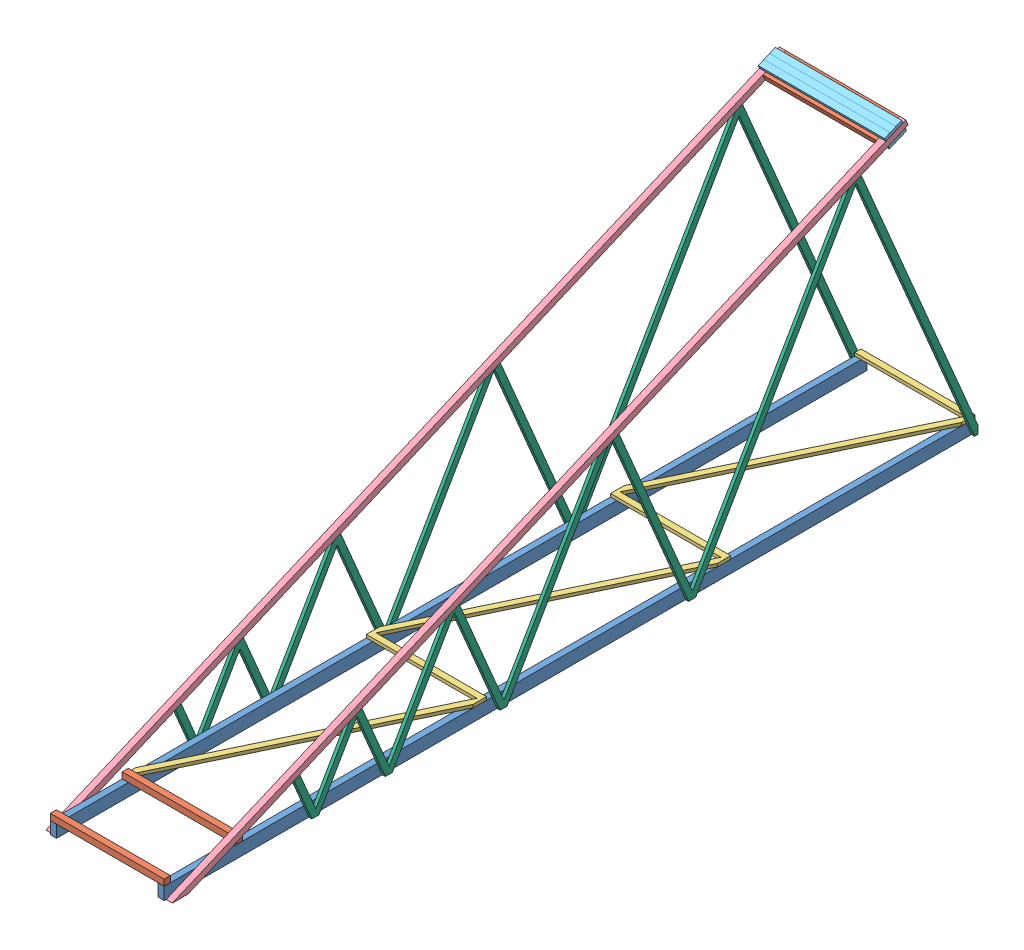
SolidWorks assembly V2 1-2, configuration Default. Lengths in mm.
Overall size (64.7 160.34 415).
20 component instances, 7 part files, 60 mates.
Components (placement in the parent):
- CompressionBeam-1: CompressionBeam [Default] at (128.4141 212.2584 116.772) size (3.17 6.35 415)
- CompressionBeam-2: CompressionBeam [Default] at (73.2391 212.2584 116.772) size (3.17 6.35 415)
- Part2^V2 1-2-1: Part2^V2 1-2 [Default] at (73.2391 212.2584 116.772) x (0 0 1) z (-1 0 0) (virtual)
- CompressionHorizontalBrace-1: CompressionHorizontalBrace [Default] at (73.2391 221.7834 531.772) x (0 -1 0) z (1 0 0) size (3.17 3.17 58.35)
- CompressionHorizontalBrace-2: CompressionHorizontalBrace [Default] at (73.2391 221.7834 494.947) x (0 -1 0) z (1 0 0) size (3.17 3.17 58.35)
- Part4^V2 1-2-1: Part4^V2 1-2 [Default] at (128.4141 218.6084 116.772) x (1 0 0) z (0 1 0) size (58.35 375 1.59) (virtual)
- Part5^V2 1-2-1: Part5^V2 1-2 [Default] at (73.2391 212.2584 116.772) x (0 0 1) z (-1 0 0) size (376.7 159.5 3.17) (virtual)
- CompressionHorizontalBrace-3: CompressionHorizontalBrace [Default] at (73.2391 369.274 161.1687) x (0 -0.920393 -0.390995) z (1 0 0) size (3.17 3.17 58.35)
- CompressionHorizontalBrace-4: CompressionHorizontalBrace [Default] at (73.2391 370.5154 158.2464) x (0 -0.920393 -0.390995) z (1 0 0) size (3.17 3.17 58.35)
- CompressionHorizontalBrace-5: CompressionHorizontalBrace [Default] at (73.2391 368.0326 164.0909) x (0 -0.920393 -0.390995) z (1 0 0) size (3.17 3.17 58.35)
- CompressionHorizontalBrace-6: CompressionHorizontalBrace [Default] at (73.2391 366.7912 167.0132) x (0 -0.920393 -0.390995) z (1 0 0) size (3.17 3.17 58.35)
- Part5^V2 1-2-2: Part5^V2 1-2 [Default] at (134.7641 212.2584 116.772) x (0 0 1) z (-1 0 0) size (376.7 159.5 3.17) (virtual)
- Part6^V2 1-2-1: Part6^V2 1-2 [Default] at (71.6516 366.621 167.4137) x (1 0 0) z (0 0.920393 0.390995) size (64.7 3.18 1.59) (virtual)
- Part6^V2 1-2-2: Part6^V2 1-2 [Default] at (71.6516 367.8625 164.4915) x (1 0 0) z (0 0.920393 0.390995) size (64.7 3.18 1.59) (virtual)
- Part6^V2 1-2-3: Part6^V2 1-2 [Default] at (71.6516 369.1039 161.5693) x (1 0 0) z (0 0.920393 0.390995) size (64.7 3.18 1.59) (virtual)
- Part6^V2 1-2-4: Part6^V2 1-2 [Default] at (71.6516 364.7205 159.7071) x (1 0 0) z (0 0.920393 0.390995) size (64.7 3.18 1.59) (virtual)
- Part6^V2 1-2-5: Part6^V2 1-2 [Default] at (71.6516 363.4791 162.6294) x (1 0 0) z (0 0.920393 0.390995) size (64.7 3.18 1.59) (virtual)
- Part6^V2 1-2-6: Part6^V2 1-2 [Default] at (71.6516 362.2377 165.5516) x (1 0 0) z (0 0.920393 0.390995) size (64.7 3.18 1.59) (virtual)
- Part7^V2 1-2-1: Part7^V2 1-2 [Default] at (131.5891 212.2584 116.772) x (0 0 -1) z (1 0 0) size (350.91 146.69 1.59) (virtual)
- Part7^V2 1-2-2: Part7^V2 1-2 [Default] at (71.6516 212.2584 116.772) x (0 0 -1) z (1 0 0) size (350.91 146.69 1.59) (virtual)
Mates (geometry in assembly coordinates):
- Distance1: distance = 52 mm: plane of CompressionBeam-1 through (128.4141 212.2584 531.772) normal (-1 0 0); plane of CompressionBeam-2 through (76.4141 212.2584 531.772) normal (1 0 0)
- Coincident2: coincident: plane of CompressionBeam-1 through (128.4141 212.2584 531.772) normal (0 0 1); plane of CompressionBeam-2 through (73.2391 212.2584 531.772) normal (0 0 1)
- InPlace1: in place: plane of ? through (73.2391 213.1549 521.772) normal (-1 0 0); plane of ? through (73.2391 0 0) normal (-1 0 0); moOrthogonalPlaneRef_w of ? through (73.2391 213.1549 521.772) normal (-1 0 0); plane of ? through (73.2391 0 0) normal (0 1 0); plane of ? through (73.2391 213.1549 521.772) normal (-1 0 0); plane of ? through (73.2391 0 0) normal (0 0 1); plane of CompressionBeam-2 through (73.2391 212.2584 531.772) normal (-1 0 0); unknown of ?
- Coincident3: coincident: plane of CompressionBeam-2; plane of Part2^V2 1-2-1
- Coincident4: coincident: moOrthogonalPlaneRef_w of CompressionBeam-2 through (73.2391 212.2584 116.772) normal (0 1 0); plane of Part2^V2 1-2-1 through (73.2391 212.2584 116.772) normal (0 1 0)
- Coincident5: coincident: moOrthogonalPlaneRef_w of CompressionBeam-2 through (73.2391 212.2584 116.772) normal (0 0 -1); plane of Part2^V2 1-2-1 through (73.2391 212.2584 116.772) normal (0 0 1)
- Coincident6: coincident: plane of CompressionBeam-1 through (131.5891 212.2584 531.772) normal (1 0 0); plane of CompressionHorizontalBrace-1 through (131.5891 221.7834 531.772) normal (1 0 0)
- Coincident7: coincident: plane of CompressionBeam-1 through (128.4141 218.6084 531.772) normal (0 1 0); plane of CompressionHorizontalBrace-1 through (131.5891 218.6084 531.772) normal (0 -1 0)
- Coincident8: coincident: plane of CompressionBeam-1 through (128.4141 212.2584 531.772) normal (0 0 1); plane of CompressionHorizontalBrace-1 through (131.5891 221.7834 531.772) normal (0 0 1)
- Coincident9: coincident: plane of CompressionBeam-2 through (73.2391 218.6084 531.772) normal (0 1 0); plane of CompressionHorizontalBrace-1 through (131.5891 218.6084 531.772) normal (0 -1 0)
- Coincident10: coincident: plane of CompressionBeam-2 through (73.2391 212.2584 531.772) normal (-1 0 0); plane of CompressionHorizontalBrace-2 through (73.2391 221.7834 494.947) normal (-1 0 0)
- Coincident11: coincident: plane of CompressionBeam-2 through (73.2391 218.6084 531.772) normal (0 1 0); plane of CompressionHorizontalBrace-2 through (131.5891 218.6084 494.947) normal (0 -1 0)
- InPlace2: in place: plane of CompressionBeam-1 through (128.4141 218.6084 521.772) normal (0 1 0); plane of ? through (0 218.6084 0) normal (0 1 0); plane of CompressionBeam-1 through (128.4141 218.6084 521.772) normal (0 1 0); plane of ? through (0 218.6084 0) normal (0 0 -1); plane of CompressionBeam-1 through (128.4141 218.6084 521.772) normal (0 1 0); plane of ? through (0 218.6084 0) normal (1 0 0); plane of CompressionBeam-1 through (128.4141 218.6084 531.772) normal (0 1 0); unknown of Part4^V2 1-2-1
- Coincident13: coincident: plane of ?; plane of Part4^V2 1-2-1
- Coincident14: coincident: moOrthogonalPlaneRef_w of CompressionBeam-1 through (128.4141 218.6084 116.772) normal (0 0 -1); plane of Part4^V2 1-2-1 through (128.4141 218.6084 116.772) normal (0 0 -1)
- Coincident15: coincident: moOrthogonalPlaneRef_w of CompressionBeam-1 through (128.4141 218.6084 116.772) normal (-1 0 0); plane of Part4^V2 1-2-1 through (128.4141 218.6084 116.772) normal (1 0 0)
- InPlace3: in place: plane of CompressionBeam-2 through (73.2391 212.2584 521.772) normal (-1 0 0); plane of ? through (73.2391 0 0) normal (-1 0 0); plane of CompressionBeam-2 through (73.2391 212.2584 521.772) normal (-1 0 0); plane of ? through (73.2391 0 0) normal (0 1 0); plane of CompressionBeam-2 through (73.2391 212.2584 521.772) normal (-1 0 0); plane of ? through (73.2391 0 0) normal (0 0 1); plane of CompressionBeam-2 through (73.2391 212.2584 531.772) normal (-1 0 0); unknown of ?
- Coincident16: coincident: plane of CompressionBeam-2; plane of Part5^V2 1-2-1
- Coincident17: coincident: moOrthogonalPlaneRef_w of CompressionBeam-2 through (73.2391 212.2584 116.772) normal (0 1 0); plane of Part5^V2 1-2-1 through (73.2391 212.2584 116.772) normal (0 1 0)
- Coincident18: coincident: moOrthogonalPlaneRef_w of CompressionBeam-2 through (73.2391 212.2584 116.772) normal (0 0 -1); plane of Part5^V2 1-2-1 through (73.2391 212.2584 116.772) normal (0 0 1)
- Coincident19: coincident: plane of CompressionHorizontalBrace-2 through (131.5891 221.7834 491.772) normal (0 0 -1); plane of Part4^V2 1-2-1 through (128.4141 220.1959 491.772) normal (0 0 1)
- Coincident20: coincident: plane of Part5^V2 1-2-1 through (73.2391 212.2584 116.772) normal (1 0 0); plane of CompressionHorizontalBrace-4 through (73.2391 370.5154 158.2464) normal (-1 0 0)
- Coincident21: coincident: plane of Part5^V2 1-2-1 through (73.2391 212.2584 116.772) normal (1 0 0); plane of CompressionHorizontalBrace-3 through (73.2391 369.274 161.1687) normal (-1 0 0)
- Coincident22: coincident: plane of Part5^V2 1-2-1 through (73.2391 212.2584 116.772) normal (1 0 0); plane of CompressionHorizontalBrace-5 through (73.2391 368.0326 164.0909) normal (-1 0 0)
- Coincident23: coincident: plane of Part5^V2 1-2-1 through (73.2391 212.2584 116.772) normal (1 0 0); plane of CompressionHorizontalBrace-6 through (73.2391 366.7912 167.0132) normal (-1 0 0)
- Coincident24: coincident: plane of CompressionHorizontalBrace-5 through (131.5891 368.0326 164.0909) normal (0 -0.390995 0.920393); plane of CompressionHorizontalBrace-6 through (131.5891 368.0326 164.0909) normal (0 0.390995 -0.920393)
- Coincident25: coincident: plane of CompressionHorizontalBrace-5 through (131.5891 365.1104 162.8495) normal (0 -0.920393 -0.390995); plane of CompressionHorizontalBrace-6 through (131.5891 363.869 165.7718) normal (0 -0.920393 -0.390995)
- Coincident26: coincident: plane of CompressionHorizontalBrace-3 through (131.5891 366.3518 159.9273) normal (0 -0.920393 -0.390995); plane of CompressionHorizontalBrace-5 through (131.5891 365.1104 162.8495) normal (0 -0.920393 -0.390995)
- Coincident27: coincident: plane of CompressionHorizontalBrace-3 through (131.5891 366.3518 159.9273) normal (0 -0.920393 -0.390995); plane of CompressionHorizontalBrace-4 through (131.5891 367.5932 157.005) normal (0 -0.920393 -0.390995)
- Coincident28: coincident: plane of CompressionHorizontalBrace-3 through (131.5891 369.274 161.1687) normal (0 -0.390995 0.920393); plane of CompressionHorizontalBrace-5 through (131.5891 369.274 161.1687) normal (0 0.390995 -0.920393)
- Coincident29: coincident: plane of CompressionHorizontalBrace-3 through (131.5891 370.5154 158.2464) normal (0 0.390995 -0.920393); plane of CompressionHorizontalBrace-4 through (131.5891 370.5154 158.2464) normal (0 -0.390995 0.920393)
- Coincident30: coincident: plane of Part5^V2 1-2-1 through (73.2391 222.7683 92.0319) normal (0 0.390995 -0.920393); plane of CompressionHorizontalBrace-4 through (131.5891 371.7568 155.3242) normal (0 0.390995 -0.920393)
- Coincident31: coincident: plane of Part5^V2 1-2-1 through (70.0641 358.3247 178.8228) normal (0 -0.920393 -0.390995); plane of CompressionHorizontalBrace-4 through (131.5891 367.5932 157.005) normal (0 -0.920393 -0.390995)
- Coincident32: coincident: plane of CompressionHorizontalBrace-4 through (131.5891 371.7568 155.3242) normal (0 0.390995 -0.920393); plane of Part5^V2 1-2-2 through (134.7641 222.7683 92.0319) normal (0 0.390995 -0.920393)
- Coincident33: coincident: plane of CompressionHorizontalBrace-6 through (131.5891 366.7912 167.0132) normal (0 0.920393 0.390995); plane of Part5^V2 1-2-2 through (131.5891 361.247 180.0642) normal (0 0.920393 0.390995)
- Coincident34: coincident: plane of CompressionHorizontalBrace-6 through (131.5891 366.7912 167.0132) normal (1 0 0); plane of Part5^V2 1-2-2 through (131.5891 212.2584 116.772) normal (-1 0 0)
- Coincident38: coincident: plane of Part6^V2 1-2-1 through (65.3775 370.1144 163.2505) normal (-1 0 0); plane of Part6^V2 1-2-2 through (65.3775 371.3559 160.3283) normal (-1 0 0)
- Coincident39: coincident: plane of Part6^V2 1-2-2 through (65.3775 371.3559 160.3283) normal (-1 0 0); plane of Part6^V2 1-2-3 through (69.7097 366.4047 168.043) normal (-1 0 0)
- Coincident40: coincident: plane of Part6^V2 1-2-1 through (65.3775 370.1144 163.2505) normal (0 0.390995 -0.920393); plane of Part6^V2 1-2-2 through (65.3775 370.1144 163.2505) normal (0 -0.390995 0.920393)
- Coincident41: coincident: plane of Part6^V2 1-2-2 through (65.3775 371.3559 160.3283) normal (0 0.390995 -0.920393); plane of Part6^V2 1-2-3 through (69.7097 365.1633 170.9652) normal (0 -0.390995 0.920393)
- Coincident42: coincident: plane of CompressionHorizontalBrace-3 through (131.5891 369.274 161.1687) normal (0 0.920393 0.390995); plane of Part6^V2 1-2-2 through (66.965 367.8625 164.4915) normal (0 -0.920393 -0.390995)
- Coincident43: coincident: plane of CompressionHorizontalBrace-4 through (131.5891 370.5154 158.2464) normal (0 0.920393 0.390995); plane of Part6^V2 1-2-3 through (71.2972 362.9113 172.2062) normal (0 -0.920393 -0.390995)
- Coincident44: coincident: plane of Part6^V2 1-2-4 through (65.3775 368.2139 155.5439) normal (-1 0 0); plane of Part6^V2 1-2-5 through (65.3775 366.9725 158.4662) normal (-1 0 0)
- Coincident45: coincident: plane of Part6^V2 1-2-5 through (65.3775 366.9725 158.4662) normal (-1 0 0); plane of Part6^V2 1-2-6 through (65.3775 365.7311 161.3884) normal (-1 0 0)
- Coincident46: coincident: plane of Part6^V2 1-2-5 through (65.3775 365.7311 161.3884) normal (0 -0.390995 0.920393); plane of Part6^V2 1-2-6 through (65.3775 365.7311 161.3884) normal (0 0.390995 -0.920393)
- Coincident47: coincident: plane of Part6^V2 1-2-4 through (65.3775 366.9725 158.4662) normal (0 -0.390995 0.920393); plane of Part6^V2 1-2-5 through (65.3775 366.9725 158.4662) normal (0 0.390995 -0.920393)
- Coincident48: coincident: plane of Part6^V2 1-2-4 through (66.965 366.1816 160.3278) normal (0 0.920393 0.390995); plane of Part6^V2 1-2-5 through (66.965 364.9402 163.2501) normal (0 0.920393 0.390995)
- Coincident49: coincident: plane of Part6^V2 1-2-5 through (66.965 364.9402 163.2501) normal (0 0.920393 0.390995); plane of Part6^V2 1-2-6 through (66.965 363.6988 166.1723) normal (0 0.920393 0.390995)
- Coincident50: coincident: plane of CompressionHorizontalBrace-6 through (131.5891 363.869 165.7718) normal (0 -0.920393 -0.390995); plane of Part6^V2 1-2-6 through (66.965 363.6988 166.1723) normal (0 0.920393 0.390995)
- Coincident51: coincident: plane of Part6^V2 1-2-3 through (69.7097 366.4047 168.043) normal (-1 0 0); plane of Part6^V2 1-2-4 through (65.3775 368.2139 155.5439) normal (-1 0 0)
- Coincident52: coincident: plane of Part6^V2 1-2-1 through (65.3775 368.873 166.1728) normal (0 -0.390995 0.920393); plane of Part6^V2 1-2-6 through (65.3775 364.4897 164.3107) normal (0 -0.390995 0.920393)
- Distance3: distance = 1.5875 mm: plane of CompressionHorizontalBrace-6 through (131.5891 366.7912 167.0132) normal (0 -0.390995 0.920393); plane of Part6^V2 1-2-6 through (70.0641 364.4897 164.3107) normal (0 -0.390995 0.920393)
- InPlace5: in place: plane of CompressionBeam-1 through (131.5891 212.2584 531.772) normal (1 0 0); plane of ? through (131.5891 0 0) normal (1 0 0); plane of CompressionBeam-1 through (131.5891 212.2584 531.772) normal (1 0 0); plane of ? through (131.5891 0 0) normal (0 1 0); plane of CompressionBeam-1 through (131.5891 212.2584 531.772) normal (1 0 0); plane of ? through (131.5891 0 0) normal (0 0 -1); plane of CompressionBeam-1 through (131.5891 212.2584 531.772) normal (1 0 0); unknown of Part7^V2 1-2-1
- Coincident54: coincident: plane of ?; plane of Part7^V2 1-2-1
- Coincident55: coincident: moOrthogonalPlaneRef_w of CompressionBeam-1 through (131.5891 212.2584 116.772) normal (0 1 0); plane of Part7^V2 1-2-1 through (131.5891 212.2584 116.772) normal (0 1 0)
- Coincident56: coincident: moOrthogonalPlaneRef_w of CompressionBeam-1 through (131.5891 212.2584 116.772) normal (0 0 1); plane of Part7^V2 1-2-1 through (131.5891 212.2584 116.772) normal (0 0 -1)
- Coincident57: coincident: plane of CompressionBeam-2 through (73.2391 212.2584 531.772) normal (-1 0 0); plane of Part7^V2 1-2-2 through (73.2391 212.2584 116.772) normal (1 0 0)
- Coincident58: coincident: plane of CompressionBeam-2 through (73.2391 212.2584 531.772) normal (0 -1 0); plane of Part7^V2 1-2-2 through (73.2391 212.2584 116.772) normal (0 -1 0)
- Coincident59: coincident: plane of CompressionBeam-2 through (73.2391 212.2584 116.772) normal (0 0 -1); plane of Part7^V2 1-2-2 through (73.2391 212.2584 116.772) normal (0 0 -1)
- Coincident60: coincident: plane of Part5^V2 1-2-1 through (70.0641 212.2584 116.772) normal (-1 0 0); plane of Part6^V2 1-2-3 through (70.0641 372.5973 157.406) normal (-1 0 0)
